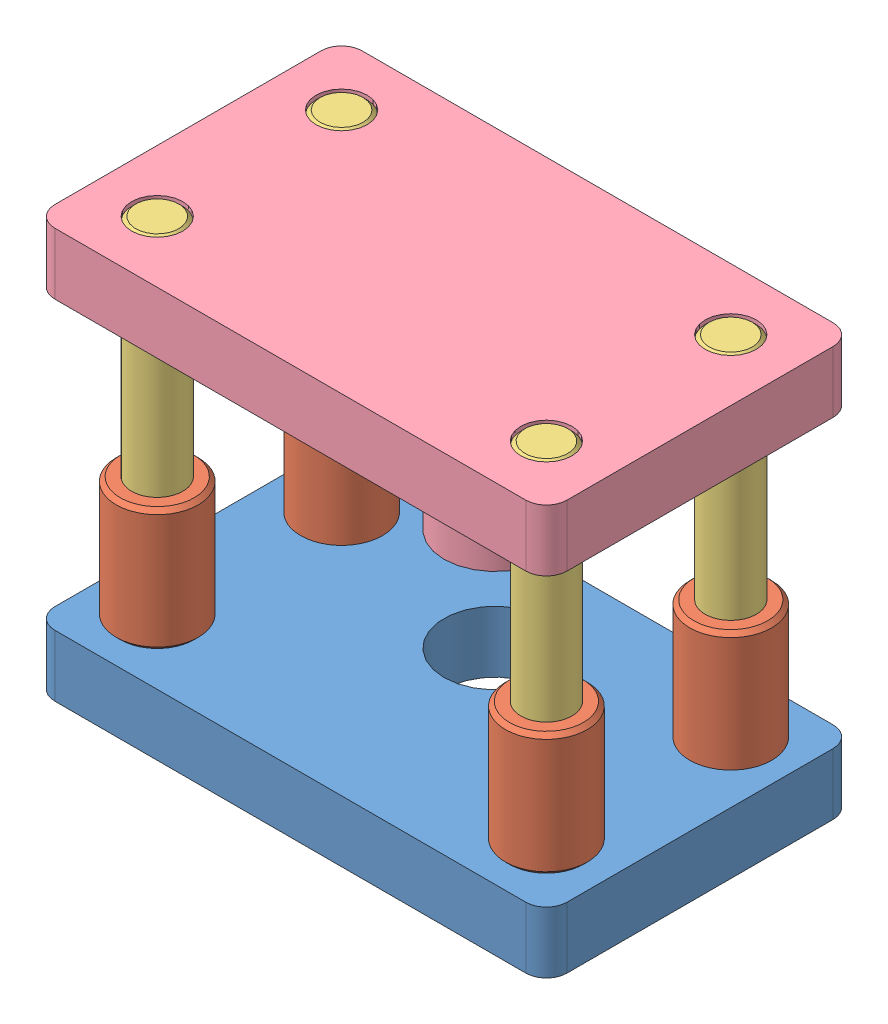
SolidWorks assembly Assem1, configuration Default. Lengths in mm.
Overall size (250 200 150).
10 component instances, 4 part files, 11 mates.
Components (placement in the parent):
- Bottom Plate-1: Bottom Plate [Default] at (112.3173 106.8068 197.943) size (250 30 150)
- Guide Bush-1: Guide Bush [Default] at (17.3173 166.8068 242.943) x (0.953616 0 -0.301026) z (0.301026 0 0.953616) size (40 60 40)
- Guide Bush-2: Guide Bush [Default] at (17.3173 164.8068 152.943) size (40 60 40)
- Guide Bush-3: Guide Bush [Default] at (207.3173 166.8068 242.943) x (0.953616 0 -0.301026) z (0.301026 0 0.953616) size (40 60 40)
- Guide Bush-4: Guide Bush [Default] at (207.3173 164.8068 152.943) size (40 60 40)
- Pillar-1: Pillar [Default] at (17.3173 206.8068 242.943) x (-0.100417 0 0.994945) z (-0.994945 0 -0.100417) size (25 200 25)
- Pillar-2: Pillar [Default] at (17.3173 206.8068 152.943) size (25 200 25)
- Pillar-3: Pillar [Default] at (207.3173 206.8068 152.943) size (25 200 25)
- Pillar-4: Pillar [Default] at (207.3173 206.8068 242.943) x (-0.100417 0 0.994945) z (-0.994945 0 -0.100417) size (25 200 25)
- Top Plate-1: Top Plate [Default] at (112.3173 306.8068 197.943) x (-1 0 0) z (0 0 1) size (250 120 150)
Mates (geometry in assembly coordinates):
- Concentric1: concentric anti-aligned: cylinder of Bottom Plate-1 through (17.3173 106.8068 242.943) axis (0 1 0) radius 12.5; cylinder of Guide Bush-1 through (17.3173 196.8068 242.943) axis (0 -1 0) radius 12.5
- Coincident1: coincident anti-aligned: plane of Bottom Plate-1 through (-2.6827 136.8068 262.943) normal (0 1 0); circle of Guide Bush-1
- Coincident2: coincident aligned: plane of Bottom Plate-1 through (-2.6827 136.8068 262.943) normal (0 1 0); circle of Guide Bush-2
- Concentric2: concentric anti-aligned: cylinder of Bottom Plate-1 through (17.3173 106.8068 152.943) axis (0 1 0) radius 12.5; cylinder of Guide Bush-2 through (17.3173 194.8068 152.943) axis (0 -1 0) radius 12.5
- Coincident3: coincident aligned: plane of Bottom Plate-1 through (-2.6827 106.8068 262.943) normal (0 -1 0); plane of Pillar-1 through (17.3173 106.8068 242.943) normal (0 -1 0)
- Concentric3: concentric aligned: cylinder of Guide Bush-1 through (17.3173 196.8068 242.943) axis (0 -1 0) radius 12.5; cylinder of Pillar-1 through (17.3173 306.8068 242.943) axis (0 -1 0) radius 12.5
- Coincident4: coincident aligned: plane of Bottom Plate-1 through (-2.6827 106.8068 262.943) normal (0 -1 0); circle of Pillar-2
- Concentric4: concentric aligned: cylinder of Guide Bush-2 through (17.3173 194.8068 152.943) axis (0 -1 0) radius 12.5; cylinder of Pillar-2 through (17.3173 306.8068 152.943) axis (0 -1 0) radius 12.5
- Coincident5: coincident aligned: circle of Bottom Plate-1; cylinder of Top Plate-1 through (112.3173 186.8068 172.943) axis (0 1 0) radius 25
- Coincident6: coincident aligned: plane of Bottom Plate-1 through (237.3173 136.8068 262.943) normal (1 0 0); plane of Top Plate-1 through (237.3173 276.8068 262.943) normal (1 0 0)
- Coincident7: coincident aligned: circle of Pillar-1; plane of Top Plate-1 through (227.3173 306.8068 262.943) normal (0 1 0)
